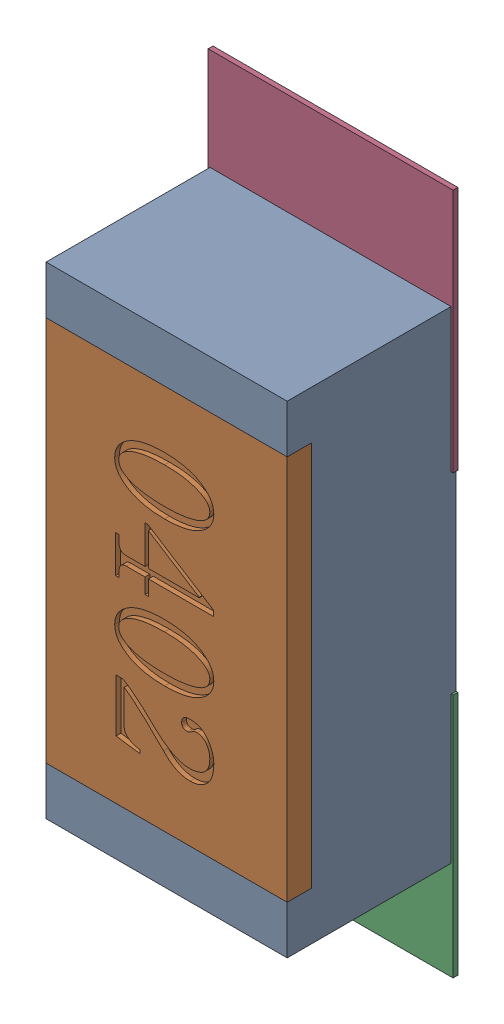
SolidWorks assembly R62, configuration Défaut. Lengths in mm.
Overall size (0.51 1.42 0.35).
5 component instances, 2 part files, 0 mates.
Components (placement in the parent):
- R0402-1: R0402 [Défaut] at (37.6681 -27.1146 0) x (0 -1 0) z (0 0 1) size (1 0.5 0.35)
- 6504207776-1: 6504207776 [Défaut] at (37.6682 -27.5646 0) size (0.51 0.51 0.01)
  - Extruded-1: Extruded [Défaut] at origin size (0.51 0.51 0.01)
- 6504207776-2: 6504207776 [Défaut] at (37.6682 -26.6575 0) size (0.51 0.51 0.01)
  - Extruded-1: Extruded [Défaut] at origin size (0.51 0.51 0.01)
